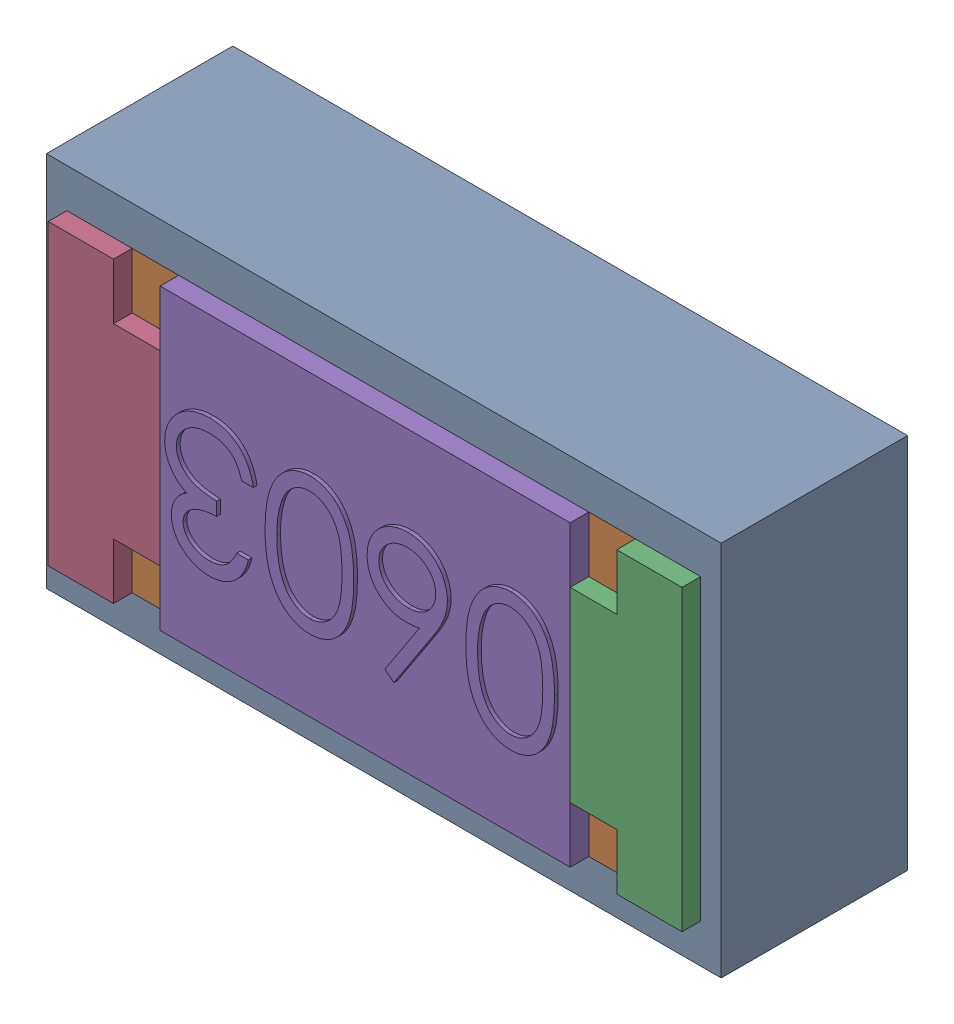
SolidWorks assembly SB12, configuration Default. Lengths in mm.
Overall size (1.81 1.01 0.56).
3 component instances, 2 part files, 0 mates.
Components (placement in the parent):
- 1088884160-1: 1088884160 [Default] at (13.125 8.1 0) size (1.81 1.01 0.5)
  - Extruded-27-1: Extruded-27 [Default] at origin size (1.81 1.01 0.5)
- R0603-1: R0603 [Default] at (13.1249 8.0999 0) x (-1 0 0) z (0 1 0) size (1.7 0.56 0.8)
